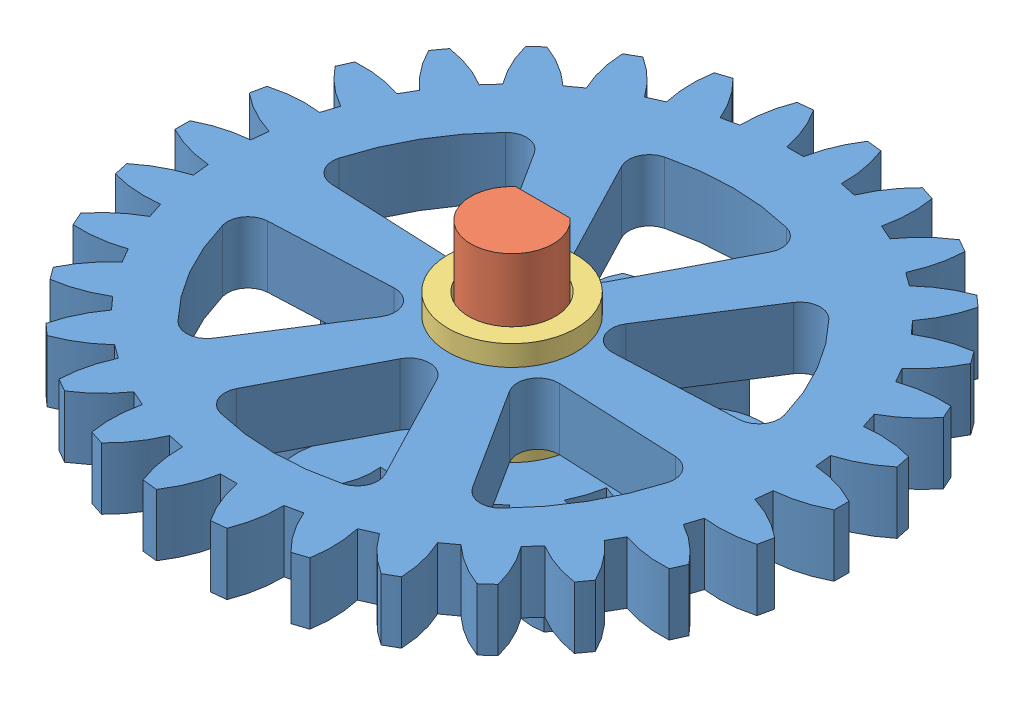
SolidWorks assembly subassem2, configuration Default. Lengths in mm.
Overall size (32 15 31.89).
6 component instances, 3 part files, 12 mates.
Components (placement in the parent):
- root_gear-3: root_gear [30T 1.0Mod] at (8.0314 5.7093 13.4022) size (32 3 31.89)
- root_gear-4: root_gear [10T 1.5Mod] at (8.0314 1.7093 13.4022) size (18 3 17.3)
- axel-1: axel [15 tall] at (8.0314 -2.2907 13.4022) size (4 15 3.5)
- spacer-1: spacer [1 mm tall] at (8.0314 0.7093 13.4022) x (-0.679343 0 -0.733821) z (0.733821 0 -0.679343) size (6.2 1 6.2)
- spacer-2: spacer [1 mm tall] at (8.0314 4.7093 13.4022) x (0.793961 0 -0.607968) z (0.607968 0 0.793961) size (6.2 1 6.2)
- spacer-3: spacer [1 mm tall] at (8.0314 8.7093 13.4022) x (0.998465 0 -0.055384) z (0.055384 0 0.998465) size (6.2 1 6.2)
Mates (geometry in assembly coordinates):
- Concentric1: concentric: cylinder of root_gear-3 through (8.0314 5.7093 13.4022) axis (0 1 0) radius 2; cylinder of axel-1 through (8.0314 12.7093 13.4022) axis (0 -1 0) radius 2
- Concentric2: concentric: cylinder of root_gear-4 through (8.0314 1.7093 13.4022) axis (0 1 0) radius 2; cylinder of axel-1 through (8.0314 12.7093 13.4022) axis (0 -1 0) radius 2
- Concentric3: concentric: cylinder of axel-1 through (8.0314 12.7093 13.4022) axis (0 -1 0) radius 2; cylinder of spacer-3 through (8.0314 8.7093 13.4022) axis (0 1 0) radius 2.1
- Concentric4: concentric: cylinder of axel-1 through (8.0314 12.7093 13.4022) axis (0 -1 0) radius 2; cylinder of spacer-1 through (8.0314 0.7093 13.4022) axis (0 1 0) radius 2.1
- Concentric5: concentric: cylinder of axel-1 through (8.0314 12.7093 13.4022) axis (0 -1 0) radius 2; cylinder of spacer-2 through (8.0314 4.7093 13.4022) axis (0 1 0) radius 2.1
- Coincident1: coincident: plane of root_gear-3 through (9.3542 5.7093 11.9022) normal (0 0 1); plane of axel-1 through (6.7085 12.7093 11.9022) normal (0 0 -1)
- Coincident2: coincident: plane of root_gear-4 through (9.3542 1.7093 11.9022) normal (0 0 1); plane of axel-1 through (6.7085 12.7093 11.9022) normal (0 0 -1)
- Coincident3: coincident: plane of root_gear-3 through (8.0314 8.7093 13.4022) normal (0 1 0); plane of spacer-3 through (8.0314 8.7093 13.4022) normal (0 -1 0)
- Coincident4: coincident: plane of root_gear-3 through (8.0314 5.7093 13.4022) normal (0 -1 0); plane of spacer-2 through (8.0314 5.7093 13.4022) normal (0 1 0)
- Coincident5: coincident: plane of root_gear-4 through (8.0314 4.7093 13.4022) normal (0 1 0); plane of spacer-2 through (8.0314 4.7093 13.4022) normal (0 -1 0)
- Coincident6: coincident: plane of root_gear-4 through (8.0314 1.7093 13.4022) normal (0 -1 0); plane of spacer-1 through (8.0314 1.7093 13.4022) normal (0 1 0)
- Distance2: distance = 3 mm: plane of axel-1 through (8.0314 -2.2907 13.4022) normal (0 -1 0); plane of spacer-1 through (8.0314 0.7093 13.4022) normal (0 -1 0)
